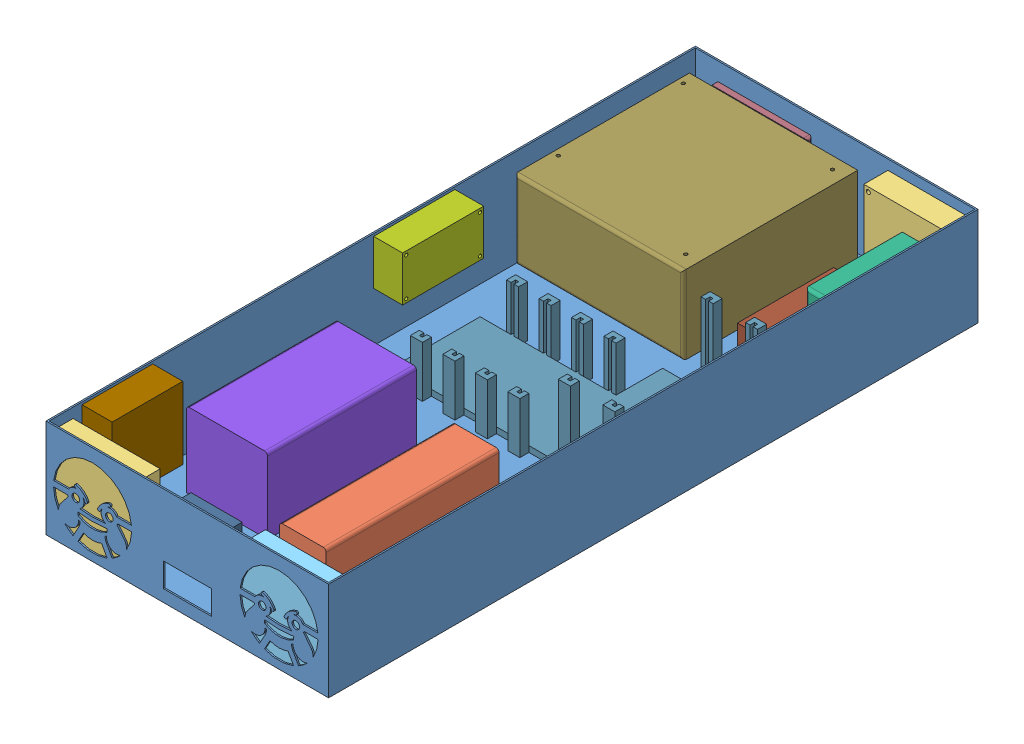
SolidWorks assembly Electronics, configuration Default. Lengths in mm.
Overall size (298.45 107.88 685.8).
20 component instances, 14 part files, 0 mates.
Components (placement in the parent):
- Copy of Electronics.CATProduct^Electronics-1: Copy of Electronics.CATProduct^Electronics [Default] at origin size (298.45 107.88 685.8) (virtual)
  - Copy of Box_Layout_V2.CATProduct^Copy of Electronics.CATProduct_Electronics-1: Copy of Box_Layout_V2.CATProduct^Copy of Electronics.CATProduct_Electronics [Default] at origin size (298.45 107.88 685.8) (virtual)
    - Copy of Enclosure2.CATPart^Copy of Box_Layout_V2.CATProduct_Copy of Electronics.CATProduct_Electronics-1: Copy of Enclosure2.CATPart^Copy of Box_Layout_V2.CATProduct_Copy of Electronics.CATProduct_Electronics [Default] at (517.435 -623.6476 -841.9006) size (298.45 107.88 685.8) (virtual)
    - Copy of Contact_Block.CATPart^Copy of Box_Layout_V2.CATProduct_Copy of Electronics.CATProduct_Electronics-1: Copy of Contact_Block.CATPart^Copy of Box_Layout_V2.CATProduct_Copy of Electronics.CATProduct_Electronics [Default] at (379.9575 -622.0601 -1110.1881) size (49.23 47.62 182.56) (virtual)
    - Copy of Fan.CATPart^Copy of Box_Layout_V2.CATProduct_Copy of Electronics.CATProduct_Electronics-1: Copy of Fan.CATPart^Copy of Box_Layout_V2.CATProduct_Copy of Electronics.CATProduct_Electronics [Default] at (423.8487 -622.0601 -1526.1131) size (92 92 25.4) (virtual)
    - Copy of USB_hub.CATPart^Copy of Box_Layout_V2.CATProduct_Copy of Electronics.CATProduct_Electronics-1: Copy of USB_hub.CATPart^Copy of Box_Layout_V2.CATProduct_Copy of Electronics.CATProduct_Electronics [Default] at (505.6875 -622.0601 -1241.2331) x (0 -1 0) z (0 0 1) size (30.48 10.16 106.68) (virtual)
    - Copy of Fan_1.CATPart^Copy of Box_Layout_V2.CATProduct_Copy of Electronics.CATProduct_Electronics-1: Copy of Fan_1.CATPart^Copy of Box_Layout_V2.CATProduct_Copy of Electronics.CATProduct_Electronics [Default] at (423.8487 -530.0613 -843.4881) x (1 0 0) z (0 0 -1) size (92 92 25.4) (virtual)
    - Copy of Fan.CATPart^Copy of Box_Layout_V2.CATProduct_Copy of Electronics.CATProduct_Electronics-2: Copy of Fan.CATPart^Copy of Box_Layout_V2.CATProduct_Copy of Electronics.CATProduct_Electronics [Default] at (220.5725 -622.0601 -868.8881) size (92 92 25.4) (virtual)
    - Copy of Network_Switch.CATPart^Copy of Box_Layout_V2.CATProduct_Copy of Electronics.CATProduct_Electronics-1: Copy of Network_Switch.CATPart^Copy of Box_Layout_V2.CATProduct_Copy of Electronics.CATProduct_Electronics [Default] at (515.8475 -622.0601 -1373.3131) x (0 0 1) z (0 -1 0) size (102.71 26.76 95.42) (virtual)
    - Copy of USB_hub.CATPart^Copy of Box_Layout_V2.CATProduct_Copy of Electronics.CATProduct_Electronics-2: Copy of USB_hub.CATPart^Copy of Box_Layout_V2.CATProduct_Copy of Electronics.CATProduct_Electronics [Default] at (515.8475 -591.5801 -1109.1531) x (0 1 0) z (0 0 1) size (30.48 10.16 106.68) (virtual)
    - Copy of USB_hub.CATPart^Copy of Box_Layout_V2.CATProduct_Copy of Electronics.CATProduct_Electronics-3: Copy of USB_hub.CATPart^Copy of Box_Layout_V2.CATProduct_Copy of Electronics.CATProduct_Electronics [Default] at (230.7325 -591.5801 -1038.4331) x (0 1 0) z (0 0 1) size (30.48 10.16 106.68) (virtual)
    - Copy of 12V_Regulator.CATPart^Copy of Box_Layout_V2.CATProduct_Copy of Electronics.CATProduct_Electronics-1: Copy of 12V_Regulator.CATPart^Copy of Box_Layout_V2.CATProduct_Copy of Electronics.CATProduct_Electronics [Default] at (220.5725 -522.1876 -1186.3881) x (0 0 1) z (0 1 0) size (85.72 30.48 47.62) (virtual)
    - Copy of Breaker.CATPart^Copy of Box_Layout_V2.CATProduct_Copy of Electronics.CATProduct_Electronics-1: Copy of Breaker.CATPart^Copy of Box_Layout_V2.CATProduct_Copy of Electronics.CATProduct_Electronics [Default] at (256.1325 -622.0601 -1110.1881) size (85.72 79.38 157.16) (virtual)
    - Copy of 24V_Converter.CATPart^Copy of Box_Layout_V2.CATProduct_Copy of Electronics.CATProduct_Electronics-1: Copy of 24V_Converter.CATPart^Copy of Box_Layout_V2.CATProduct_Copy of Electronics.CATProduct_Electronics [Default] at (252.3225 -522.1876 -878.4004) x (0 1 0) z (0 0 1) size (76.2 31.75 74.63) (virtual)
    - Copy of 5V_Converter.CATPart^Copy of Box_Layout_V2.CATProduct_Copy of Electronics.CATProduct_Electronics-1: Copy of 5V_Converter.CATPart^Copy of Box_Layout_V2.CATProduct_Copy of Electronics.CATProduct_Electronics [Default] at (331.6975 -622.0601 -885.5632) size (53.98 19.05 63.75) (virtual)
    - Copy of Arduino.CATPart^Copy of Box_Layout_V2.CATProduct_Copy of Electronics.CATProduct_Electronics-1: Copy of Arduino.CATPart^Copy of Box_Layout_V2.CATProduct_Copy of Electronics.CATProduct_Electronics [Default] at (470.7975 -596.6601 -1475.3131) x (1 0 0) z (0 0 -1) size (53.34 25.4 101.6) (virtual)
    - Copy of Computer_Assembly.CATProduct^Copy of Box_Layout_V2.CATProduct_Copy of Electronics.CATProduct_Electronics-1: Copy of Computer_Assembly.CATProduct^Copy of Box_Layout_V2.CATProduct_Copy of Electronics.CATProduct_Electronics [Default] at (324.6385 -581.5712 -1409.7656) x (0 0 1) z (-1 0 0) size (191.92 84.8 179.22) (virtual)
      - Copy of Computer.CATPart^Copy of Computer_Assembly.CATProduct_Copy of Box_Layout_V2.CATProduct_Copy of Electronics.CATProduct_Electronics-1: Copy of Computer.CATPart^Copy of Computer_Assembly.CATProduct_Copy of Box_Layout_V2.CATProduct_Copy of Electronics.CATProduct_Electronics [Default] at (67.8025 -40.4888 104.066) size (184.86 83.31 179.22) (virtual)
      - Copy of SSD.CATPart^Copy of Computer_Assembly.CATProduct_Copy of Box_Layout_V2.CATProduct_Copy of Electronics.CATProduct_Electronics-1: Copy of SSD.CATPart^Copy of Computer_Assembly.CATProduct_Copy of Box_Layout_V2.CATProduct_Copy of Electronics.CATProduct_Electronics [Default] at (-116.3475 7.9679 30.2535) x (0 -1 0) z (0 0 1) size (71.27 7.11 100.71) (virtual)
    - Copy of Motor_Controller_Mount.CATPart^Copy of Box_Layout_V2.CATProduct_Copy of Electronics.CATProduct_Electronics-1: Copy of Motor_Controller_Mount.CATPart^Copy of Box_Layout_V2.CATProduct_Copy of Electronics.CATProduct_Electronics [Default] at (500.6075 -622.0601 -1321.3383) x (0 0 -1) z (1 0 0) size (160.35 92.08 243.84) (virtual)
